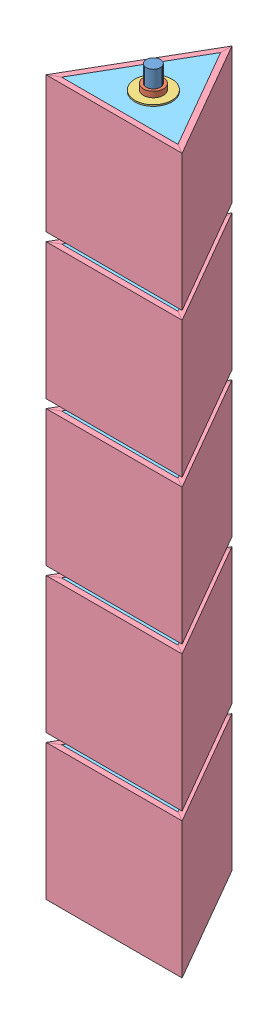
SolidWorks assembly rod_assembled, configuration Default. Lengths in mm.
Overall size (348 1708.15 364.2).
81 component instances, 6 part files, 17 mates.
Components (placement in the parent):
- rod-1: rod [Default] at (977.2141 709.9151 2218.518) size (31.75 1708.15 31.75)
- collar-1: collar [Default] at (977.2141 748.0151 2218.518) size (44.45 12.7 44.45)
- washer-1: washer [Default] at (977.2141 760.7151 2218.518) size (82.55 3.17 82.55)
- triangle-1: triangle [Default] at (859.8458 525.4427 2574.5415) x (1 0 0) z (0 1 0) size (348 364.2 304.8)
  - triangle_face-1: triangle_face [Default] at (-35.0317 268.0353 238.4474) size (304.8 12.7 304.8)
  - triangle_face-2: triangle_face [Default] at (117.3683 531.9998 238.4474) x (-0.5 -0.866025 0) z (0 0 1) size (304.8 12.7 304.8)
  - triangle_face-3: triangle_face [Default] at (269.7683 268.0353 238.4474) x (-0.5 0.866025 0) z (0 0 1) size (304.8 12.7 304.8)
  - triangle_top_bot-1: triangle_top_bot [Default] at (269.7683 268.0353 238.4474) x (0.5 -0.866025 0) z (0 0 -1) size (260.81 225.86 12.7)
  - triangle_top_bot-2: triangle_top_bot [Default] at (269.7683 268.0353 543.2474) size (260.81 225.86 12.7)
  - triangle_inside_corner-1: triangle_inside_corner [Default] at (53.355 472.7151 492.4474) x (0.5 -0.866025 0) z (-0.866025 -0.5 0) size (83.58 38.1 72.38)
  - triangle_inside_corner-2: triangle_inside_corner [Default] at (48.317 242.2404 492.4474) x (0.5 0.866025 0) z (0.866025 -0.5 0) size (83.58 38.1 72.38)
  - triangle_inside_corner-3: triangle_inside_corner [Default] at (225.5462 242.2404 492.4474) x (0.5 0.866025 0) z (0.866025 -0.5 0) size (83.58 38.1 72.38)
  - triangle_inside_corner-4: triangle_inside_corner [Default] at (48.317 242.2404 251.1474) x (0.5 0.866025 0) z (0.866025 -0.5 0) size (83.58 38.1 72.38)
  - triangle_inside_corner-6: triangle_inside_corner [Default] at (225.5462 242.2404 251.1474) x (0.5 0.866025 0) z (0.866025 -0.5 0) size (83.58 38.1 72.38)
  - triangle_inside_corner-7: triangle_inside_corner [Default] at (53.355 472.7151 251.1474) x (0.5 -0.866025 0) z (-0.866025 -0.5 0) size (83.58 38.1 72.38)
- triangle_and_washers-1: triangle_and_washers [Default] at (0 323.85 0) size (348 323.85 364.2)
  - collar-1: collar [Default] at (977.2141 748.0151 2218.518) size (44.45 12.7 44.45)
  - washer-1: washer [Default] at (977.2141 760.7151 2218.518) size (82.55 3.17 82.55)
  - triangle-1: triangle [Default] at (859.8458 525.4427 2574.5415) x (1 0 0) z (0 1 0) size (348 364.2 304.8)
    - triangle_face-1: triangle_face [Default] at (-35.0317 268.0353 238.4474) size (304.8 12.7 304.8)
    - triangle_face-2: triangle_face [Default] at (117.3683 531.9998 238.4474) x (-0.5 -0.866025 0) z (0 0 1) size (304.8 12.7 304.8)
    - triangle_face-3: triangle_face [Default] at (269.7683 268.0353 238.4474) x (-0.5 0.866025 0) z (0 0 1) size (304.8 12.7 304.8)
    - triangle_top_bot-1: triangle_top_bot [Default] at (269.7683 268.0353 238.4474) x (0.5 -0.866025 0) z (0 0 -1) size (260.81 225.86 12.7)
    - triangle_top_bot-2: triangle_top_bot [Default] at (269.7683 268.0353 543.2474) size (260.81 225.86 12.7)
    - triangle_inside_corner-1: triangle_inside_corner [Default] at (53.355 472.7151 492.4474) x (0.5 -0.866025 0) z (-0.866025 -0.5 0) size (83.58 38.1 72.38)
    - triangle_inside_corner-2: triangle_inside_corner [Default] at (48.317 242.2404 492.4474) x (0.5 0.866025 0) z (0.866025 -0.5 0) size (83.58 38.1 72.38)
    - triangle_inside_corner-3: triangle_inside_corner [Default] at (225.5462 242.2404 492.4474) x (0.5 0.866025 0) z (0.866025 -0.5 0) size (83.58 38.1 72.38)
    - triangle_inside_corner-4: triangle_inside_corner [Default] at (48.317 242.2404 251.1474) x (0.5 0.866025 0) z (0.866025 -0.5 0) size (83.58 38.1 72.38)
    - triangle_inside_corner-6: triangle_inside_corner [Default] at (225.5462 242.2404 251.1474) x (0.5 0.866025 0) z (0.866025 -0.5 0) size (83.58 38.1 72.38)
    - triangle_inside_corner-7: triangle_inside_corner [Default] at (53.355 472.7151 251.1474) x (0.5 -0.866025 0) z (-0.866025 -0.5 0) size (83.58 38.1 72.38)
  - washer-2: washer [Default] at (977.2141 744.8401 2218.518) size (82.55 3.17 82.55)
- triangle_and_washers-2: triangle_and_washers [Default] at (0 647.7 0) size (348 323.85 364.2)
  - collar-1: collar [Default] at (977.2141 748.0151 2218.518) size (44.45 12.7 44.45)
  - washer-1: washer [Default] at (977.2141 760.7151 2218.518) size (82.55 3.17 82.55)
  - triangle-1: triangle [Default] at (859.8458 525.4427 2574.5415) x (1 0 0) z (0 1 0) size (348 364.2 304.8)
    - triangle_face-1: triangle_face [Default] at (-35.0317 268.0353 238.4474) size (304.8 12.7 304.8)
    - triangle_face-2: triangle_face [Default] at (117.3683 531.9998 238.4474) x (-0.5 -0.866025 0) z (0 0 1) size (304.8 12.7 304.8)
    - triangle_face-3: triangle_face [Default] at (269.7683 268.0353 238.4474) x (-0.5 0.866025 0) z (0 0 1) size (304.8 12.7 304.8)
    - triangle_top_bot-1: triangle_top_bot [Default] at (269.7683 268.0353 238.4474) x (0.5 -0.866025 0) z (0 0 -1) size (260.81 225.86 12.7)
    - triangle_top_bot-2: triangle_top_bot [Default] at (269.7683 268.0353 543.2474) size (260.81 225.86 12.7)
    - triangle_inside_corner-1: triangle_inside_corner [Default] at (53.355 472.7151 492.4474) x (0.5 -0.866025 0) z (-0.866025 -0.5 0) size (83.58 38.1 72.38)
    - triangle_inside_corner-2: triangle_inside_corner [Default] at (48.317 242.2404 492.4474) x (0.5 0.866025 0) z (0.866025 -0.5 0) size (83.58 38.1 72.38)
    - triangle_inside_corner-3: triangle_inside_corner [Default] at (225.5462 242.2404 492.4474) x (0.5 0.866025 0) z (0.866025 -0.5 0) size (83.58 38.1 72.38)
    - triangle_inside_corner-4: triangle_inside_corner [Default] at (48.317 242.2404 251.1474) x (0.5 0.866025 0) z (0.866025 -0.5 0) size (83.58 38.1 72.38)
    - triangle_inside_corner-6: triangle_inside_corner [Default] at (225.5462 242.2404 251.1474) x (0.5 0.866025 0) z (0.866025 -0.5 0) size (83.58 38.1 72.38)
    - triangle_inside_corner-7: triangle_inside_corner [Default] at (53.355 472.7151 251.1474) x (0.5 -0.866025 0) z (-0.866025 -0.5 0) size (83.58 38.1 72.38)
  - washer-2: washer [Default] at (977.2141 744.8401 2218.518) size (82.55 3.17 82.55)
- triangle_and_washers-3: triangle_and_washers [Default] at (0 1295.4 0) size (348 323.85 364.2)
  - collar-1: collar [Default] at (977.2141 748.0151 2218.518) size (44.45 12.7 44.45)
  - washer-1: washer [Default] at (977.2141 760.7151 2218.518) size (82.55 3.17 82.55)
  - triangle-1: triangle [Default] at (859.8458 525.4427 2574.5415) x (1 0 0) z (0 1 0) size (348 364.2 304.8)
    - triangle_face-1: triangle_face [Default] at (-35.0317 268.0353 238.4474) size (304.8 12.7 304.8)
    - triangle_face-2: triangle_face [Default] at (117.3683 531.9998 238.4474) x (-0.5 -0.866025 0) z (0 0 1) size (304.8 12.7 304.8)
    - triangle_face-3: triangle_face [Default] at (269.7683 268.0353 238.4474) x (-0.5 0.866025 0) z (0 0 1) size (304.8 12.7 304.8)
    - triangle_top_bot-1: triangle_top_bot [Default] at (269.7683 268.0353 238.4474) x (0.5 -0.866025 0) z (0 0 -1) size (260.81 225.86 12.7)
    - triangle_top_bot-2: triangle_top_bot [Default] at (269.7683 268.0353 543.2474) size (260.81 225.86 12.7)
    - triangle_inside_corner-1: triangle_inside_corner [Default] at (53.355 472.7151 492.4474) x (0.5 -0.866025 0) z (-0.866025 -0.5 0) size (83.58 38.1 72.38)
    - triangle_inside_corner-2: triangle_inside_corner [Default] at (48.317 242.2404 492.4474) x (0.5 0.866025 0) z (0.866025 -0.5 0) size (83.58 38.1 72.38)
    - triangle_inside_corner-3: triangle_inside_corner [Default] at (225.5462 242.2404 492.4474) x (0.5 0.866025 0) z (0.866025 -0.5 0) size (83.58 38.1 72.38)
    - triangle_inside_corner-4: triangle_inside_corner [Default] at (48.317 242.2404 251.1474) x (0.5 0.866025 0) z (0.866025 -0.5 0) size (83.58 38.1 72.38)
    - triangle_inside_corner-6: triangle_inside_corner [Default] at (225.5462 242.2404 251.1474) x (0.5 0.866025 0) z (0.866025 -0.5 0) size (83.58 38.1 72.38)
    - triangle_inside_corner-7: triangle_inside_corner [Default] at (53.355 472.7151 251.1474) x (0.5 -0.866025 0) z (-0.866025 -0.5 0) size (83.58 38.1 72.38)
  - washer-2: washer [Default] at (977.2141 744.8401 2218.518) size (82.55 3.17 82.55)
- triangle_and_washers-4: triangle_and_washers [Default] at (0 971.55 0) size (348 323.85 364.2)
  - collar-1: collar [Default] at (977.2141 748.0151 2218.518) size (44.45 12.7 44.45)
  - washer-1: washer [Default] at (977.2141 760.7151 2218.518) size (82.55 3.17 82.55)
  - triangle-1: triangle [Default] at (859.8458 525.4427 2574.5415) x (1 0 0) z (0 1 0) size (348 364.2 304.8)
    - triangle_face-1: triangle_face [Default] at (-35.0317 268.0353 238.4474) size (304.8 12.7 304.8)
    - triangle_face-2: triangle_face [Default] at (117.3683 531.9998 238.4474) x (-0.5 -0.866025 0) z (0 0 1) size (304.8 12.7 304.8)
    - triangle_face-3: triangle_face [Default] at (269.7683 268.0353 238.4474) x (-0.5 0.866025 0) z (0 0 1) size (304.8 12.7 304.8)
    - triangle_top_bot-1: triangle_top_bot [Default] at (269.7683 268.0353 238.4474) x (0.5 -0.866025 0) z (0 0 -1) size (260.81 225.86 12.7)
    - triangle_top_bot-2: triangle_top_bot [Default] at (269.7683 268.0353 543.2474) size (260.81 225.86 12.7)
    - triangle_inside_corner-1: triangle_inside_corner [Default] at (53.355 472.7151 492.4474) x (0.5 -0.866025 0) z (-0.866025 -0.5 0) size (83.58 38.1 72.38)
    - triangle_inside_corner-2: triangle_inside_corner [Default] at (48.317 242.2404 492.4474) x (0.5 0.866025 0) z (0.866025 -0.5 0) size (83.58 38.1 72.38)
    - triangle_inside_corner-3: triangle_inside_corner [Default] at (225.5462 242.2404 492.4474) x (0.5 0.866025 0) z (0.866025 -0.5 0) size (83.58 38.1 72.38)
    - triangle_inside_corner-4: triangle_inside_corner [Default] at (48.317 242.2404 251.1474) x (0.5 0.866025 0) z (0.866025 -0.5 0) size (83.58 38.1 72.38)
    - triangle_inside_corner-6: triangle_inside_corner [Default] at (225.5462 242.2404 251.1474) x (0.5 0.866025 0) z (0.866025 -0.5 0) size (83.58 38.1 72.38)
    - triangle_inside_corner-7: triangle_inside_corner [Default] at (53.355 472.7151 251.1474) x (0.5 -0.866025 0) z (-0.866025 -0.5 0) size (83.58 38.1 72.38)
  - washer-2: washer [Default] at (977.2141 744.8401 2218.518) size (82.55 3.17 82.55)
- washer-2: washer [Default] at (977.2141 2364.0901 2218.518) size (82.55 3.17 82.55)
- collar-2: collar [Default] at (977.2141 2367.2651 2218.518) size (44.45 12.7 44.45)
Mates (geometry in assembly coordinates):
- Concentric1: concentric aligned: circle of collar-1; circle of washer-1
- Concentric2: concentric aligned: circle of rod-1; circle of washer-1
- Distance1: distance = 38.1 mm aligned: plane of collar-1 through (977.2141 748.0151 2218.518) normal (0 -1 0); plane of rod-1 through (977.2141 709.9151 2218.518) normal (0 -1 0)
- Coincident2: coincident anti-aligned: plane of collar-1 through (977.2141 760.7151 2218.518) normal (0 1 0); plane of washer-1 through (977.2141 760.7151 2218.518) normal (0 -1 0)
- Coincident3: coincident anti-aligned: plane of washer-1 through (977.2141 763.8901 2218.518) normal (0 1 0); plane of triangle-1/triangle_top_bot-1 through (1129.6141 763.8901 2306.5062) normal (0 -1 0)
- Concentric4: concentric anti-aligned: cylinder of rod-1 through (977.2141 2418.0651 2218.518) axis (0 -1 0) radius 15.875; circle of triangle_and_washers-1/collar-1
- Coincident5: coincident anti-aligned: plane of triangle-1/triangle_top_bot-2 through (1129.6141 1068.6901 2306.5062) normal (0 1 0); plane of triangle_and_washers-1/washer-2 through (977.2141 1068.6901 2218.518) normal (0 -1 0)
- Coincident6: coincident anti-aligned: cylinder of rod-1 through (977.2141 2418.0651 2218.518) axis (0 -1 0) radius 15.875; circle of triangle_and_washers-2/washer-2
- Coincident7: coincident anti-aligned: plane of triangle_and_washers-1/triangle-1/triangle_top_bot-2 through (1129.6141 1392.5401 2306.5062) normal (0 1 0); plane of triangle_and_washers-2/washer-2 through (977.2141 1392.5401 2218.518) normal (0 -1 0)
- Coincident8: coincident anti-aligned: plane of triangle_and_washers-2/triangle-1/triangle_top_bot-2 through (1129.6141 1716.3901 2306.5062) normal (0 1 0); plane of triangle_and_washers-4/washer-2 through (977.2141 1716.3901 2218.518) normal (0 -1 0)
- Coincident9: coincident anti-aligned: cylinder of rod-1 through (977.2141 2418.0651 2218.518) axis (0 -1 0) radius 15.875; circle of triangle_and_washers-4/washer-2
- Coincident10: coincident anti-aligned: cylinder of rod-1 through (977.2141 2418.0651 2218.518) axis (0 -1 0) radius 15.875; circle of triangle_and_washers-3/washer-2
- Coincident11: coincident anti-aligned: plane of triangle_and_washers-3/washer-2 through (977.2141 2040.2401 2218.518) normal (0 -1 0); plane of triangle_and_washers-4/triangle-1/triangle_top_bot-2 through (1129.6141 2040.2401 2306.5062) normal (0 1 0)
- Coincident12: coincident anti-aligned: cylinder of rod-1 through (977.2141 2418.0651 2218.518) axis (0 -1 0) radius 15.875; circle of washer-2
- Coincident13: coincident anti-aligned: plane of triangle_and_washers-3/triangle-1/triangle_top_bot-2 through (1129.6141 2364.0901 2306.5062) normal (0 1 0); plane of washer-2 through (977.2141 2364.0901 2218.518) normal (0 -1 0)
- Coincident14: coincident anti-aligned: cylinder of rod-1 through (977.2141 2418.0651 2218.518) axis (0 -1 0) radius 15.875; circle of collar-2
- Coincident15: coincident anti-aligned: plane of washer-2 through (977.2141 2367.2651 2218.518) normal (0 1 0); plane of collar-2 through (977.2141 2367.2651 2218.518) normal (0 -1 0)
